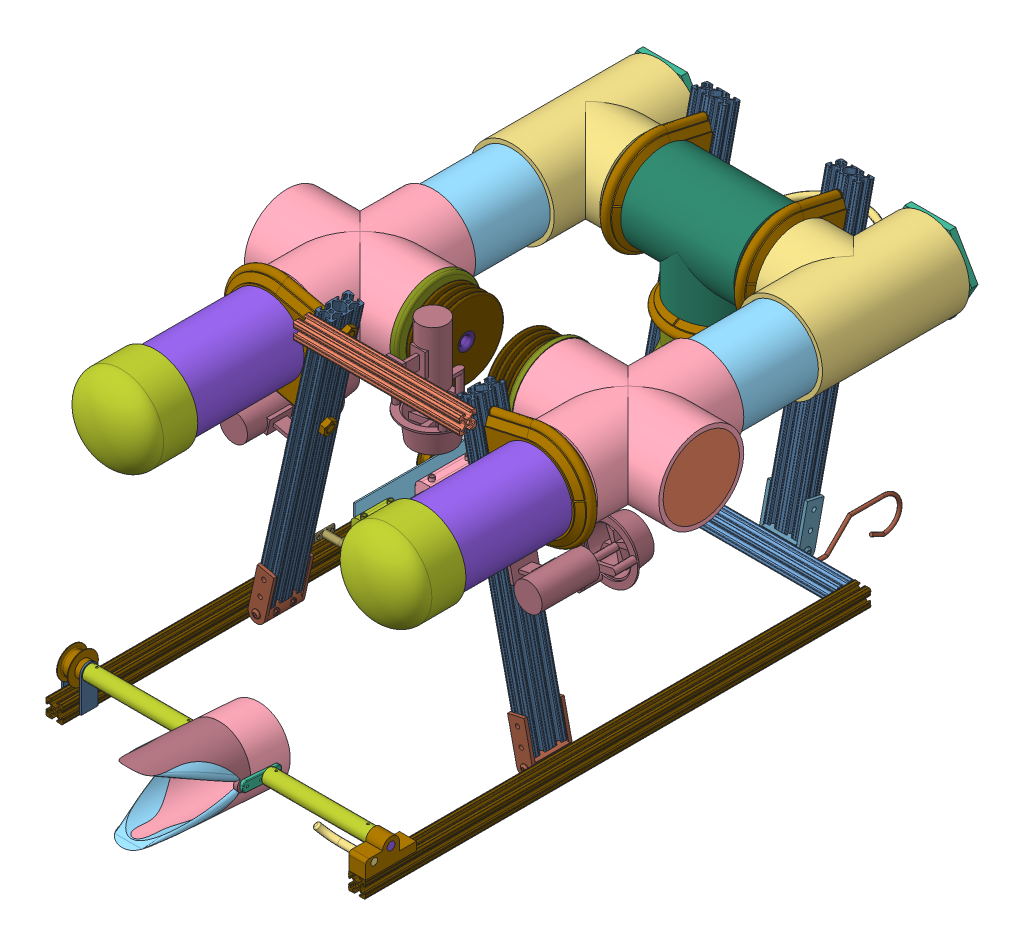
SolidWorks assembly Final_Model, configuration Default. Lengths in mm.
Overall size (623.28 474.95 1127.75).
98 component instances, 49 part files, 198 mates.
Components (placement in the parent):
- Camera-1: Camera [Default] at origin size (90 50 31)
- Camera_Lense-1: Camera_Lense [Default] at (45 25 12.5) size (114.76 114.76 10)
- PVC_Tee-2: PVC_Tee [4880K48] at (246.6576 226.6068 -97.99) x (0 0 1) z (0 -1 0) size (221.03 148.72 127.2)
- PVC_Tee-3: PVC_Tee [4880K48] at (-156.6576 226.6068 -97.99) x (0 0 -1) z (0 -1 0) size (221.03 148.72 127.2)
- PVC_Cross-1: PVC_Cross [4880K249] at (246.6576 226.6068 241.1708) x (1 -0.000013 0) z (0.000013 1 0) size (219.96 219.96 127.76)
- PVC_Cross-2: PVC_Cross [4880K249] at (-156.6576 226.6068 241.1708) x (1 0 0) z (0 1 0) size (219.96 219.96 127.76)
- Camera-2: Camera [Default] at (344.1393 201.6055 286.1708) x (0 0 -1) z (1 -0.000013 0) size (90 50 31)
- Camera_Lense-2: Camera_Lense [Default] at (346.6396 226.6055 241.1708) x (0 0 1) z (-1 0.000013 0) size (114.76 114.76 10)
- Camera-3: Camera [Default] at (-254.1396 201.6068 196.1708) x (0 0 1) z (-1 0 0) size (90 50 31)
- Camera_Lense-3: Camera_Lense [Default] at (-266.6396 226.6068 241.1708) x (0 0 1) z (-1 0 0) size (114.76 114.76 10)
- PVC_Pipe_SmallGap-1: PVC_Pipe_SmallGap [48925K98] at (-156.6576 226.6068 71.4888) size (114.3 114.3 221)
- PVC_Pipe_SmallGap-2: PVC_Pipe_SmallGap [48925K98] at (246.6576 226.6068 71.4888) x (-0.871628 0.490169 0) z (0 0 1) size (114.3 114.3 221)
- PVC_EndCap_Hex-1: PVC_EndCap_Hex [4880K851] at (246.6576 226.6068 -187.8679) x (0 0 -1) z (0.866025 -0.5 0) size (60.32 133.82 115.89)
- PVC_EndCap_Hex-2: PVC_EndCap_Hex [4880K851] at (-156.6576 226.6068 -187.8679) x (0 0 -1) z (0.866025 0.5 0) size (60.32 133.82 115.89)
- PVC_EndCap_Circle-3: PVC_EndCap_Circle [4880K58] at (-156.6576 226.6068 593.444) x (0 0 1) z (0.824445 0.565942 0) size (88.8 127.64 127.64)
- PVC_EndCap_Circle-4: PVC_EndCap_Circle [4880K58] at (246.6576 226.6068 593.444) x (0 0 1) z (0.198256 0.98015 0) size (88.8 127.64 127.64)
- PVC_Pipe_MedGap-1: PVC_Pipe_MedGap [48925K98] at (-156.6576 226.6068 450.3528) size (114.3 114.3 300)
- PVC_Pipe_MedGap-2: PVC_Pipe_MedGap [48925K98] at (246.6576 226.6068 450.3528) size (114.3 114.3 300)
- Ubolt_Clamp-1: Ubolt_Clamp [3176T41] at (-55.8634 205.2169 -194.7131) x (0 -0.976409 0.215928) z (-1 0 0) size (161.7 175.58 31.5)
- Ubolt_Clamp-2: Ubolt_Clamp [3176T41] at (145.8634 205.2169 -194.7131) x (0 0.976409 -0.215928) z (1 0 0) size (161.7 175.58 31.5)
- Ubolt_Clamp-3: Ubolt_Clamp [3176T41] at (-59.9348 205.2157 366.9008) x (-0.215941 -0.976406 0) z (0 0 -1) size (161.7 175.58 31.5)
- Ubolt_Clamp-4: Ubolt_Clamp [3176T41] at (149.9345 205.2169 366.9008) x (0.215928 -0.976409 0) z (0 0 1) size (161.7 175.58 31.5)
- 8020_Vertical_Bar-1: 8020_Vertical_Bar [47065T213] at (-154.2406 -116.7666 379.6008) x (0 0 -1) z (0.215941 0.976406 0) size (50.88 25.48 430)
- 8020_Vertical_Bar-2: 8020_Vertical_Bar [47065T213] at (244.236 -116.7665 354.2008) x (0 0 1) z (-0.215928 0.976409 0) size (50.88 25.48 430)
- 8020_Vertical_Bar-3: 8020_Vertical_Bar [47065T213] at (133.1634 -116.7665 -100.4116) x (1 0 0) z (0 0.976409 -0.215928) size (50.88 25.48 430)
- 8020_Vertical_Bar-4: 8020_Vertical_Bar [47065T213] at (-43.1634 -116.7665 -100.4116) x (-1 0 0) z (0 0.976409 -0.215928) size (50.88 25.48 430)
- 8020_Front_Hinge-1: 8020_Front_Hinge [47065T192] at (-156.8545 -130.0147 366.5923) x (-0.000013 -1 0) z (0 0 1) size (77.44 42.62 66.61)
- 8020_Front_Hinge-2: 8020_Front_Hinge [47065T192] at (246.8498 -130.0147 366.5923) x (0 -1 0) z (0 0 -1) size (77.44 42.62 66.61)
- Ubolt_Clamp-5: Ubolt_Clamp [3176T41] at (45 125.838 -197.05) x (1 0 0) z (0 -1 0) size (161.7 175.58 31.5)
- 8020_Rear_Thruster_Bar-1: 8020_Rear_Thruster_Bar [47065T213] at (-49.75 138.538 -174.4985) x (0 -1 0) z (1 0 0) size (50.88 25.6 169.85)
- Thruster-1: Thruster [Default] at (45.25 92.1765 -245.3518) x (1 0 0) z (0 -1 0) size (91 103.34 158.7)
- 8020_Rear_Hinge-1: 8020_Rear_Hinge [47065T192] at (-56.1719 -130.0147 -97.7978) x (0 1 0) z (-1 0 0) size (77.44 42.62 66.61)
- 8020_Rear_Hinge-2: 8020_Rear_Hinge [47065T192] at (146.1719 -130.0147 -97.7978) x (0 1 0) z (-1 0 0) size (77.44 42.62 66.61)
- PVC_Rear_Tee-1: PVC_Rear_Tee [4880K48] at (45 226.6068 -97.99) x (-1 0 0) z (0 0 1) size (170.23 148.72 127.2)
- PVC_Rear_Elbow-1: PVC_Rear_Elbow [4880K28] at (45 25 -97.99) x (0 0 -1) z (1 0 0) size (173.99 148.59 127)
- PVC_Pipe_Rear-1: PVC_Pipe_Rear [48925K98] at (45 125.778 -97.99) x (0.999631 0 -0.027178) z (0 1 0) size (114.3 114.3 83.7)
- PVC_Pipe_Rear-2: PVC_Pipe_Rear [48925K98] at (-55.8288 226.6068 -97.99) x (0 0 -1) z (1 0 0) size (114.3 114.3 83.7)
- PVC_Pipe_Rear-3: PVC_Pipe_Rear [48925K98] at (145.8288 226.6068 -97.99) x (0 -0.326039 -0.945356) z (1 0 0) size (114.3 114.3 83.7)
- 8020_Horizontal_Bar_Long-1: 8020_Horizontal_Bar_Long [47065T121] at (272.5583 -129.9315 294.9022) x (-1 0 0) z (0 0 -1) size (25.48 25.48 760)
- 8020_Horizontal_Bar_Long-2: 8020_Horizontal_Bar_Long [47065T121] at (-182.563 -130.3228 294.9022) x (-1 0.000013 0) z (0 0 -1) size (25.48 25.48 760)
- 8020_Rear_Bar-1: 8020_Rear_Bar [47065T121] at (44.9998 -129.9315 -72.6063) x (0 0 -1) z (1 0 0) size (25.48 25.48 429.1)
- 8020_Front_Thruster_Bar-1: 8020_Front_Thruster_Bar [47065T121] at (45.0956 287.4796 405.6178) x (0 0 1) z (-1 0.000013 0) size (25.48 25.48 250)
- Thruster-2: Thruster [Default] at (46.3449 241.1181 334.7645) x (1 -0.000013 0) z (-0.000013 -1 0) size (91 103.34 158.7)
- Thruster-3: Thruster [Default] at (266.4534 110.9017 324.7393) x (0.215928 -0.976409 0) z (0 0 -1) size (91 103.34 158.7)
- Thruster-4: Thruster [Default] at (-176.4549 110.902 324.7393) x (0.215941 0.976406 0) z (0 0 -1) size (91 103.34 158.7)
- Rear_Thruster_Protector_Bar-3: Rear_Thruster_Protector_Bar [Default] at (-25.1 146.5465 -192.507) size (150.2 10 130.1)
- Rear_Thruster_Protector_Bar-4: Rear_Thruster_Protector_Bar [Default] at (-25.1 105.1295 -192.507) size (150.2 10 130.1)
- Beakassem-1: Beakassem [Default] at (31.099 -354.5443 692.4929) x (-1 0 0) z (0 -0.071631 -0.997431) size (427.7 101.75 206.93)
  - bottombeaktube-3: bottombeaktube [Default] at (-15.2178 266.4346 -125.0001) size (101.75 101.75 206.93)
  - beakgums-3: beakgums [Default] at (-15.2178 266.4346 -125.0001) size (101.75 50.35 132.84)
  - cupbarconnector-1: cupbarconnector [Default] at (-66.0928 250.081 42.166) x (-1 0 0) z (0 0 -1) size (25 15 58.1)
  - cupbarconnector-2: cupbarconnector [Default] at (35.6572 282.7881 42.166) x (1 0 0) z (0 0 -1) size (25 15 58.1)
  - beakshaft-1: beakshaft [Default] at (40.6572 266.4346 36.6999) size (157.97 22 22)
  - beakshaft-2: beakshaft [Default] at (-229.0678 266.4346 36.6999) size (157.97 22 22)
- beakshaftrod-1: beakshaftrod [Default] at (285.5668 -91.423 636.8022) size (50.8 12 12)
- beakshaftholder-1: beakshaftholder [Default] at (260.1668 -91.423 636.8022) size (25.4 38.2 76.2)
- beakendcap-1: beakendcap [Default] at (46.3168 -94.0591 600.0968) x (0.980812 -0.194455 0.013965) z (0 0.071631 0.997431) size (89.8 89.8 10)
- Hook-1: Hook [Default] at (196.3344 -129.8147 -77.1148) x (0 -1 0) z (-1 0 0) size (55 142.87 5)
- Hook-2: Hook [Default] at (-103.6656 -129.8147 -77.1148) x (0 -1 0) z (-1 0 0) size (55 142.87 5)
- electronics_plate2-1: electronics_plate2 [Default] at (-18.4284 -61.9406 7.3582) x (0.558849 0.829269 0) z (0 0 1) size (90 20.96 469.2)
  - electronics_plate-2: electronics_plate [Default] at (117.0343 251.6082 591.6759) size (90 6.35 469.2)
  - ArduinoMega-2: ArduinoMega [Default] at (180.3262 259.6092 300.8759) x (0 0 -1) z (0 -1 0) size (107.95 53.42 12.95)
  - motor_controller-1: motor_controller [Default] at (140.6563 260.1796 216.7494) x (0 0 -1) z (1 0 0) size (58.55 14.61 47.24)
  - motor_controller-2: motor_controller [Default] at (140.6563 260.1796 385.2964) x (0 0 -1) z (1 0 0) size (58.55 14.61 47.24)
  - Accelerometer-1: Accelerometer [Default] at (196.2343 263.3582 197.7882) x (0 0 -1) z (1 0 0) size (39.4 10.8 21.6)
- heatsinkassem-1: heatsinkassem [Default] at (-27.1485 162.2777 98.211) size (60 145.3 145.3)
  - heatsinkcaps-1: heatsinkcaps [Default] at (-29.5271 64.3291 142.9598) size (20 129.7 129.7)
  - heatsinkbar-1: heatsinkbar [Default] at (-19.5271 64.3291 142.9598) size (50 25.4 25.4)
  - heatsinkdisc-1: heatsinkdisc [Default] at (-4.5271 64.3291 142.9598) x (1 0 0) z (0 -0.002531 0.999997) size (5 114.3 114.3)
  - heatsinkdisc-2: heatsinkdisc [Default] at (5.4729 64.3291 142.9598) x (1 0 0) z (0 -0.32571 0.94547) size (5 114.3 114.3)
  - heatsinkdisc-3: heatsinkdisc [Default] at (15.4729 64.3291 142.9598) x (1 0 0) z (0 -0.122449 0.992475) size (5 114.3 114.3)
  - heatsinkdisc-4: heatsinkdisc [Default] at (25.4729 64.3291 142.9598) x (1 0 0) z (0 -0.013398 0.99991) size (5 114.3 114.3)
- heatsinkassem-2: heatsinkassem [Default] at (117.1499 334.1715 355.2145) x (-1 0.000013 0) z (-0.000012 -0.924225 -0.381849) size (60 145.3 145.3)
  - heatsinkcaps-1: heatsinkcaps [Default] at (-29.5271 64.3291 142.9598) size (20 129.7 129.7)
  - heatsinkbar-1: heatsinkbar [Default] at (-19.5271 64.3291 142.9598) size (50 25.4 25.4)
  - heatsinkdisc-1: heatsinkdisc [Default] at (-4.5271 64.3291 142.9598) x (1 0 0) z (0 -0.002531 0.999997) size (5 114.3 114.3)
  - heatsinkdisc-2: heatsinkdisc [Default] at (5.4729 64.3291 142.9598) x (1 0 0) z (0 -0.32571 0.94547) size (5 114.3 114.3)
  - heatsinkdisc-3: heatsinkdisc [Default] at (15.4729 64.3291 142.9598) x (1 0 0) z (0 -0.122449 0.992475) size (5 114.3 114.3)
  - heatsinkdisc-4: heatsinkdisc [Default] at (25.4729 64.3291 142.9598) x (1 0 0) z (0 -0.013398 0.99991) size (5 114.3 114.3)
- beakcamera-1: beakcamera [Default] at (46.3168 -91.1938 639.994) x (-1 0 0) z (0 0.071631 0.997431) size (32 32 18.5)
- cam_extender-1: cam_extender [Default] at (46.3168 -93.3428 610.0711) x (1 -0.000009 0.000001) z (0 0.071631 0.997431) size (10 10 30)
- Sensor String Hook-1: Sensor String Hook [Default] at (285.5668 -95.0499 664.9022) x (-1 0 0) z (0 0.58 -0.814616) size (81.1 24.09 10.56)
- doublepiston1_2-1: doublepiston1_2 [Default] at (-149.5251 -180.8148 114.2685) x (-1 0.000013 0) z (0 0 -1) size (34.49 70 193)
  - piston2cylinder-1: piston2cylinder [Default] at (-14.4452 85 1.8662) size (30 35 85)
  - Lbracket-1: Lbracket [Default] at (-14.9529 40 69.3662) size (2 70 193)
- cyl2shaft-1: cyl2shaft [Default] at (-150.0789 -95.8148 196.5674) x (0.938347 -0.345695 0) z (0 0 -1) size (10 10 60.8)
- cyl1-1: cyl1 [Default] at (-135.1932 -95.815 221.5674) x (-1 0.000013 0) z (0 0 -1) size (30 35 60)
- cyl1shaft-1: cyl1shaft [Default] at (-150.1932 -95.8148 270.078) x (0.942292 0.334793 0) z (0 0 -1) size (10 10 35.4)
- pistonwheel-1: pistonwheel [Default] at (-178.5332 -91.423 636.8022) x (-1 0 0) z (0 0.722827 -0.691029) size (24.5 46 46)
- beakshaftrod-2: beakshaftrod [Default] at (-146.2332 -91.423 636.8022) x (1 0 0) z (0 0.000013 1) size (50.8 12 12)
- Piston_Side_Rod_Holder-1: Piston_Side_Rod_Holder [Default] at (-197.0332 -91.423 636.8022) x (0 -0.000206 -1) z (1 0 0) size (25.4 62.7 2.5)
- Piston_Side_Rod_Holder-2: Piston_Side_Rod_Holder [Default] at (-170.0332 -91.423 636.8022) x (0 -0.000206 -1) z (1 0 0) size (25.4 62.7 2.5)
- pistonwheel-2: pistonwheel [Default] at (-178.071 -91.3314 95.768) x (-1 0.000013 0) z (0 0 1) size (24.5 46 46)
- Piston_Side_Rod_Holder-3: Piston_Side_Rod_Holder [Default] at (-196.571 -91.3311 95.768) x (0 0 -1) z (1 -0.000013 0) size (25.4 62.7 2.5)
- pistonbeltconnector-3: pistonbeltconnector [Default] at (-165.0788 -90.8146 54.9022) x (-0.000013 -1 0) z (0 0 1) size (10 22.49 30)
- pistonbeltconnector2-1: pistonbeltconnector2 [Default] at (-175.1933 -100.8144 280.078) x (0.000013 1 0) z (0 0 -1) size (10 32.49 30)
- topbeak2-1: topbeak2 [Default] at (46.3168 -79.8402 798.0869) x (1 0 0) z (0 -0.071631 -0.997431) size (101.75 60.88 147.43)
- beakgums-1: beakgums [Default] at (46.3168 -79.8402 798.0869) x (1 0 0) z (0 -0.071631 -0.997431) size (101.75 50.35 132.84)
Mates (geometry in assembly coordinates):
- Perpendicular3: perpendicular: plane of PVC_Cross-1 through (310.5386 226.606 351.1528) normal (0 0 1); plane of PVC_Cross-2 through (-46.6756 226.6068 305.0518) normal (1 0 0)
- Distance4: distance = 12.5 mm aligned: plane of Camera-2 through (344.1393 201.6055 286.1708) normal (1 -0.000013 0); plane of PVC_Cross-1 through (356.6396 226.6054 305.0518) normal (1 -0.000013 0)
- Concentric17: concentric anti-aligned: circle of PVC_Cross-1; circle of Camera-2
- Perpendicular4: perpendicular: plane of PVC_Cross-1 through (356.6396 226.6054 305.0518) normal (1 -0.000013 0); plane of Camera-2 through (314.1393 201.6059 196.1708) normal (0 0 -1)
- Coincident30: coincident aligned: plane of PVC_Cross-1 through (356.6396 226.6054 305.0518) normal (1 -0.000013 0); plane of Camera_Lense-2 through (356.6396 226.6054 241.1708) normal (1 -0.000013 0)
- Concentric18: concentric aligned: cone of PVC_Cross-1 through (356.6396 226.6054 241.1708) axis (-1 0.000013 0); cylinder of Camera_Lense-2 through (356.6396 226.6054 241.1708) axis (-1 0.000013 0) radius 57.3785
- Distance5: distance = 12.5 mm aligned: plane of Camera-3 through (-254.1396 201.6068 196.1708) normal (-1 0 0); plane of PVC_Cross-2 through (-266.6396 226.6068 305.0518) normal (-1 0 0)
- Concentric19: concentric aligned: circle of PVC_Cross-2; circle of Camera-3
- Perpendicular5: perpendicular: plane of PVC_Cross-2 through (-266.6396 226.6068 305.0518) normal (-1 0 0); plane of Camera-3 through (-224.1396 201.6068 196.1708) normal (0 0 -1)
- Coincident33: coincident aligned: plane of PVC_Cross-2 through (-266.6396 226.6068 305.0518) normal (-1 0 0); plane of Camera_Lense-3 through (-266.6396 226.6068 241.1708) normal (-1 0 0)
- Concentric20: concentric anti-aligned: cone of PVC_Cross-2 through (-215.8396 226.6068 241.1708) axis (1 0 0); cylinder of Camera_Lense-3 through (-256.6396 226.6068 241.1708) axis (-1 0 0) radius 57.3785
- Coincident34: coincident anti-aligned: plane of PVC_Tee-3 through (-156.6576 226.6068 -39.0112) normal (0 0 1); plane of PVC_Pipe_SmallGap-1 through (-156.6576 226.6068 -39.0112) normal (0 0 -1)
- Concentric21: concentric aligned: cone of PVC_Tee-3 through (-156.6576 226.6068 -39.0112) axis (0 0 -1); cylinder of PVC_Pipe_SmallGap-1 through (-156.6576 226.6068 181.9888) axis (0 0 -1) radius 57.15
- Coincident35: coincident anti-aligned: plane of PVC_Cross-2 through (-156.6576 226.6068 181.9888) normal (0 0 -1); plane of PVC_Pipe_SmallGap-1 through (-156.6576 226.6068 181.9888) normal (0 0 1)
- Concentric22: concentric anti-aligned: cone of PVC_Cross-2 through (-156.6576 226.6068 131.1888) axis (0 0 1); cylinder of PVC_Pipe_SmallGap-1 through (-156.6576 226.6068 181.9888) axis (0 0 -1) radius 57.15
- Concentric23: concentric aligned: cone of PVC_Tee-2 through (246.6576 226.6068 12.5254) axis (0 0 -1); cylinder of PVC_Pipe_SmallGap-2 through (246.6576 226.6068 181.9888) axis (0 0 -1) radius 57.15
- Coincident36: coincident anti-aligned: plane of PVC_Tee-2 through (246.6576 226.6068 -39.0112) normal (0 0 1); plane of PVC_Pipe_SmallGap-2 through (246.6576 226.6068 -39.0112) normal (0 0 -1)
- Coincident37: coincident anti-aligned: plane of PVC_Cross-1 through (246.6576 226.6068 181.9888) normal (0 0 -1); plane of PVC_Pipe_SmallGap-2 through (246.6576 226.6068 181.9888) normal (0 0 1)
- Concentric24: concentric anti-aligned: cone of PVC_Cross-1 through (246.6576 226.6068 131.1888) axis (0 0 1); cylinder of PVC_Pipe_SmallGap-2 through (246.6576 226.6068 181.9888) axis (0 0 -1) radius 57.15
- Concentric25: concentric aligned: cone of PVC_Tee-3 through (-156.6576 226.6068 -208.5054) axis (0 0 1); cylinder of PVC_EndCap_Hex-2 through (-156.6576 226.6068 -157.7054) axis (0 0 1) radius 57.15
- Coincident38: coincident anti-aligned: plane of PVC_Tee-3 through (-220.2592 226.6068 -208.5054) normal (0 0 -1); plane of PVC_EndCap_Hex-2 through (-190.1114 284.5505 -208.5054) normal (0 0 1)
- Parallel6: parallel aligned: plane of Camera-1 through (0 50 -30) normal (0 1 0); plane of PVC_EndCap_Hex-2 through (-190.1114 284.5505 -208.5054) normal (0 1 0)
- Concentric26: concentric aligned: cone of PVC_Tee-2 through (246.6576 226.6068 -156.9688) axis (0 0 1); cylinder of PVC_EndCap_Hex-1 through (246.6576 226.6068 -157.7054) axis (0 0 1) radius 57.15
- Coincident43: coincident anti-aligned: plane of PVC_Tee-2 through (310.2592 226.6068 -208.5054) normal (0 0 -1); plane of PVC_EndCap_Hex-1 through (280.1114 284.5505 -208.5054) normal (0 0 1)
- Coincident44: coincident aligned: plane of PVC_EndCap_Hex-1 through (213.2038 284.5505 -208.5054) normal (0 1 0); plane of PVC_EndCap_Hex-2 through (-190.1114 284.5505 -208.5054) normal (0 1 0)
- Concentric36: concentric aligned: cone of PVC_Cross-2 through (-156.6576 226.6068 300.3528) axis (0 0 -1); cylinder of PVC_Pipe_MedGap-1 through (-156.6576 226.6068 600.3528) axis (0 0 -1) radius 57.15
- Concentric37: concentric anti-aligned: cone of PVC_EndCap_Circle-3 through (-156.6576 226.6068 600.3528) axis (0 0 1); cylinder of PVC_Pipe_MedGap-1 through (-156.6576 226.6068 600.3528) axis (0 0 -1) radius 57.15
- Coincident55: coincident anti-aligned: circle of PVC_EndCap_Circle-3; plane of PVC_Pipe_MedGap-1 through (-156.6576 226.6068 600.3528) normal (0 0 1)
- Coincident56: coincident anti-aligned: plane of PVC_Cross-2 through (-156.6576 226.6068 300.3528) normal (0 0 1); plane of PVC_Pipe_MedGap-1 through (-156.6576 226.6068 300.3528) normal (0 0 -1)
- Concentric38: concentric aligned: cone of PVC_Cross-1 through (246.6576 226.6068 300.3528) axis (0 0 -1); cylinder of PVC_Pipe_MedGap-2 through (246.6576 226.6068 600.3528) axis (0 0 -1) radius 57.15
- Concentric39: concentric anti-aligned: cone of PVC_EndCap_Circle-4 through (246.6576 226.6068 600.3528) axis (0 0 1); cylinder of PVC_Pipe_MedGap-2 through (246.6576 226.6068 600.3528) axis (0 0 -1) radius 57.15
- Coincident57: coincident anti-aligned: circle of PVC_EndCap_Circle-4; plane of PVC_Pipe_MedGap-2 through (246.6576 226.6068 600.3528) normal (0 0 1)
- Coincident58: coincident anti-aligned: plane of PVC_Cross-1 through (246.6576 226.6068 300.3528) normal (0 0 1); plane of PVC_Pipe_MedGap-2 through (246.6576 226.6068 300.3528) normal (0 0 -1)
- Parallel7: parallel aligned: plane of Ubolt_Clamp-1 through (-55.8634 144.6932 -144.9094) normal (0 -0.215928 -0.976409); plane of Ubolt_Clamp-2 through (145.8634 281.0975 -175.0746) normal (0 -0.215928 -0.976409)
- Concentric46: concentric anti-aligned: cylinder of PVC_Pipe_MedGap-2 through (246.6576 226.6068 600.3528) axis (0 0 -1) radius 57.15; cylinder of Ubolt_Clamp-4 through (246.6576 226.6068 351.1528) axis (0 0 1) radius 57.15
- Concentric47: concentric aligned: cylinder of PVC_Pipe_MedGap-1 through (-156.6576 226.6068 600.3528) axis (0 0 -1) radius 57.15; cylinder of Ubolt_Clamp-3 through (-156.6576 226.6068 382.6488) axis (0 0 -1) radius 57.15
- Parallel12: parallel aligned: plane of Ubolt_Clamp-3 through (-155.972 229.7069 382.6488) normal (0 0 1); plane of Ubolt_Clamp-4 through (233.7273 285.0764 382.6488) normal (0 0 1)
- Concentric48: concentric anti-aligned: circle of Ubolt_Clamp-3; cylinder of 8020_Vertical_Bar-1 through (-54.4704 275.545 366.9008) axis (-0.976406 0.215941 0) radius 6.75
- Distance7: distance = 8.5 mm anti-aligned: plane of 8020_Vertical_Bar-1 through (-65.7879 304.0617 380.7161) normal (-0.976406 0.215941 0); plane of Ubolt_Clamp-3 through (-109.7393 144.6925 366.9008) normal (0.976406 -0.215941 0)
- Parallel13: parallel aligned: plane of Ubolt_Clamp-3 through (-155.972 229.7069 382.6488) normal (0 0 1); plane of 8020_Vertical_Bar-1 through (-60.2968 302.8473 384.1093) normal (0 0 1)
- Concentric49: concentric anti-aligned: circle of Ubolt_Clamp-4; cylinder of 8020_Vertical_Bar-2 through (144.471 275.5463 366.9008) axis (0.976409 0.215928 0) radius 6.75
- Distance8: distance = 8.5 mm anti-aligned: plane of 8020_Vertical_Bar-2 through (155.789 304.0629 353.0855) normal (0.976409 0.215928 0); plane of Ubolt_Clamp-4 through (199.7382 144.6932 366.9008) normal (-0.976409 -0.215928 0)
- Parallel14: parallel aligned: plane of Ubolt_Clamp-4 through (245.972 229.7069 351.1528) normal (0 0 -1); plane of 8020_Vertical_Bar-2 through (150.2978 302.8486 349.6923) normal (0 0 -1)
- Concentric50: concentric anti-aligned: circle of Ubolt_Clamp-2; cylinder of 8020_Vertical_Bar-3 through (145.8634 281.0309 -175.3758) axis (0 -0.215928 -0.976409) radius 6.75
- Distance9: distance = 8.5 mm anti-aligned: plane of 8020_Vertical_Bar-3 through (159.6787 304.0629 -188.8586) normal (0 0.215928 0.976409); plane of Ubolt_Clamp-2 through (145.8634 281.0975 -175.0746) normal (0 -0.215928 -0.976409)
- Parallel15: parallel aligned: plane of Ubolt_Clamp-2 through (130.1154 223.5067 -97.3044) normal (-1 0 0); plane of 8020_Vertical_Bar-3 through (128.6549 303.3302 -192.1718) normal (-1 0 0)
- Concentric51: concentric anti-aligned: circle of Ubolt_Clamp-1; cylinder of 8020_Vertical_Bar-4 through (-55.8634 275.5463 -200.1766) axis (0 0.215928 0.976409) radius 6.75
- Distance10: distance = 8.5 mm anti-aligned: plane of 8020_Vertical_Bar-4 through (-69.6787 304.0629 -188.8586) normal (0 0.215928 0.976409); plane of Ubolt_Clamp-1 through (-55.8634 144.6932 -144.9094) normal (0 -0.215928 -0.976409)
- Parallel16: parallel aligned: plane of Ubolt_Clamp-1 through (-71.6114 285.0764 -110.9203) normal (-1 0 0); plane of 8020_Vertical_Bar-4 through (-73.0719 302.8486 -194.3498) normal (-1 0 0)
- Parallel17: parallel aligned: plane of 8020_Vertical_Bar-3 through (132.0481 302.1159 -197.6629) normal (0 -0.215928 -0.976409); plane of 8020_Vertical_Bar-4 through (-42.0481 302.1159 -197.6629) normal (0 -0.215928 -0.976409)
- Distance11: distance = 100 mm: moEndPointRef_w of 8020_Vertical_Bar-2; plane of PVC_Cross-1 through (356.6396 226.6054 305.0518) normal (1 -0.000013 0)
- Distance12: distance = 100 mm: plane of PVC_Cross-2 through (-266.6396 226.6068 305.0518) normal (-1 0 0); moEndPointRef_w of 8020_Vertical_Bar-1
- Distance13: distance = 8.5 mm anti-aligned: plane of 8020_Front_Hinge-1 through (-156.8545 -130.0147 341.1923) normal (0 0 1); plane of 8020_Vertical_Bar-1 through (-60.2968 302.8473 349.6923) normal (0 0 -1)
- Distance14: distance = 50 mm anti-aligned: plane of 8020_Front_Hinge-1 through (-155.5426 -65.2704 396.7548) normal (0.215941 0.976406 0); plane of 8020_Vertical_Bar-1 through (-164.4833 -114.5013 390.091) normal (-0.215941 -0.976406 0)
- Distance15: distance = 8.5 mm aligned: plane of 8020_Front_Hinge-1 through (-130.7419 -70.7553 396.7548) normal (0.976406 -0.215941 0); plane of 8020_Vertical_Bar-1 through (-56.9837 302.1146 380.7161) normal (0.976406 -0.215941 0)
- Distance16: distance = 8.5 mm anti-aligned: plane of 8020_Front_Hinge-2 through (246.8498 -130.0147 341.1923) normal (0 0 1); plane of 8020_Vertical_Bar-2 through (150.2978 302.8486 349.6923) normal (0 0 -1)
- Distance17: distance = 50 mm anti-aligned: plane of 8020_Front_Hinge-2 through (245.5388 -65.2704 336.4298) normal (-0.215928 0.976409 0); plane of 8020_Vertical_Bar-2 through (254.4788 -114.5014 343.7106) normal (0.215928 -0.976409 0)
- Distance18: distance = 8.5 mm aligned: plane of 8020_Front_Hinge-2 through (220.738 -70.755 336.4298) normal (-0.976409 -0.215928 0); plane of 8020_Vertical_Bar-2 through (146.9847 302.1159 353.0855) normal (-0.976409 -0.215928 0)
- Parallel19: parallel aligned: plane of PVC_EndCap_Hex-2 through (-156.6576 226.6068 -218.0304) normal (0 0 -1); plane of Ubolt_Clamp-5 through (114.85 125.838 -161.49) normal (0 0 -1)
- Concentric53: concentric anti-aligned: circle of Ubolt_Clamp-5; cylinder of 8020_Rear_Thruster_Bar-1 through (114.85 125.838 -161.7985) axis (0 0 -1) radius 6.75
- Parallel20: parallel aligned: plane of Ubolt_Clamp-5 through (41.825 141.586 -97.99) normal (0 1 0); plane of 8020_Rear_Thruster_Bar-1 through (140.25 143.0465 -173.3832) normal (0 1 0)
- Distance25: distance = 8.5 mm anti-aligned: plane of 8020_Rear_Thruster_Bar-1 through (140.25 139.6533 -169.99) normal (0 0 1); plane of Ubolt_Clamp-5 through (114.85 125.838 -161.49) normal (0 0 -1)
- Distance26: distance = 8.5 mm anti-aligned: plane of Thruster-1 through (45.25 92.1765 -187.507) normal (0 0 1); plane of 8020_Rear_Thruster_Bar-1 through (140.25 112.0227 -179.007) normal (0 0 -1)
- Distance27: distance = 8.5 mm aligned: plane of Thruster-1 through (32.75 151.5465 -187.507) normal (0 1 0); plane of 8020_Rear_Thruster_Bar-1 through (140.25 143.0465 -173.3832) normal (0 1 0)
- Distance31: distance = 8.5 mm anti-aligned: plane of 8020_Vertical_Bar-4 through (-73.0719 302.8486 -194.3498) normal (-1 0 0); plane of 8020_Rear_Hinge-1 through (-81.5719 -130.0147 -97.7978) normal (1 0 0)
- Distance29: distance = 50 mm anti-aligned: plane of 8020_Rear_Hinge-1 through (-86.3344 -70.755 -123.9096) normal (0 0.976409 -0.215928); plane of 8020_Vertical_Bar-4 through (-32.6732 -114.5014 -90.1688) normal (0 -0.976409 0.215928)
- Distance30: distance = 8.5 mm aligned: plane of 8020_Rear_Hinge-1 through (-26.0094 -132.757 -110.1982) normal (0 -0.215928 -0.976409); plane of 8020_Vertical_Bar-4 through (-69.6787 302.1159 -197.6629) normal (0 -0.215928 -0.976409)
- Distance33: distance = 50 mm anti-aligned: plane of 8020_Rear_Hinge-2 through (176.3344 -70.755 -123.9096) normal (0 0.976409 -0.215928); plane of 8020_Vertical_Bar-3 through (122.6732 -119.0317 -110.6543) normal (0 -0.976409 0.215928)
- Distance34: distance = 8.5 mm aligned: plane of 8020_Rear_Hinge-2 through (176.3344 -132.757 -110.1982) normal (0 -0.215928 -0.976409); plane of 8020_Vertical_Bar-3 through (159.6787 302.1159 -197.6629) normal (0 -0.215928 -0.976409)
- Coincident99: coincident anti-aligned: plane of PVC_Cross-2 through (-92.7766 226.6068 351.1528) normal (0 0 1); plane of Ubolt_Clamp-3 through (-143.7265 285.0763 351.1528) normal (0 0 -1)
- Coincident100: coincident anti-aligned: plane of PVC_Cross-1 through (310.5386 226.606 351.1528) normal (0 0 1); plane of Ubolt_Clamp-4 through (245.972 229.7069 351.1528) normal (0 0 -1)
- Coincident110: coincident aligned: circle of Camera_Lense-1; plane of PVC_Rear_Elbow-1 through (45 -38.5 12.5) normal (0 0 1)
- Concentric58: concentric anti-aligned: cylinder of Camera_Lense-1 through (45 25 2.5) axis (0 0 1) radius 57.3785; cone of PVC_Rear_Elbow-1 through (45 25 -39.062) axis (0 0 -1)
- Perpendicular6: perpendicular: plane of Ubolt_Clamp-2 through (130.1154 223.5067 -97.3044) normal (-1 0 0); plane of PVC_Rear_Elbow-1 through (45 -38.5 12.5) normal (0 0 1)
- Distance35: distance = 12.5 mm aligned: plane of Camera-1 through (0 0 0) normal (0 0 1); plane of PVC_Rear_Elbow-1 through (45 -38.5 12.5) normal (0 0 1)
- Concentric59: concentric aligned: circle of Camera-1; circle of PVC_Rear_Elbow-1
- Concentric60: concentric aligned: cone of PVC_Rear_Elbow-1 through (45 135.49 -97.99) axis (0 -1 0); cylinder of PVC_Pipe_Rear-1 through (45 167.628 -97.99) axis (0 -1 0) radius 57.15
- Coincident115: coincident anti-aligned: plane of PVC_Rear_Elbow-1 through (45 83.928 -97.99) normal (0 1 0); plane of PVC_Pipe_Rear-1 through (45 83.928 -97.99) normal (0 -1 0)
- Coincident116: coincident anti-aligned: plane of Ubolt_Clamp-5 through (-14.8823 110.09 -97.99) normal (0 -1 0); plane of PVC_Rear_Elbow-1 through (45 110.09 -97.99) normal (0 1 0)
- Coincident117: coincident anti-aligned: plane of PVC_Rear_Tee-1 through (45 167.628 -97.99) normal (0 -1 0); plane of PVC_Pipe_Rear-1 through (45 167.628 -97.99) normal (0 1 0)
- Parallel26: parallel anti-aligned: plane of 8020_Rear_Thruster_Bar-1 through (140.25 112.0227 -179.007) normal (0 0 -1); plane of PVC_Rear_Elbow-1 through (45 -38.5 12.5) normal (0 0 1)
- Concentric61: concentric aligned: cylinder of Ubolt_Clamp-5 through (45 141.586 -97.99) axis (0 -1 0) radius 57.15; cylinder of PVC_Pipe_Rear-1 through (45 167.628 -97.99) axis (0 -1 0) radius 57.15
- Concentric62: concentric anti-aligned: cone of PVC_Rear_Tee-1 through (45 116.0914 -97.99) axis (0 1 0); cylinder of PVC_Pipe_Rear-1 through (45 167.628 -97.99) axis (0 -1 0) radius 57.15
- Concentric64: concentric aligned: cone of PVC_Tee-3 through (-46.1422 226.6068 -97.99) axis (-1 0 0); cylinder of PVC_Pipe_Rear-2 through (-13.9788 226.6068 -97.99) axis (-1 0 0) radius 57.15
- Concentric65: concentric aligned: cylinder of Ubolt_Clamp-1 through (-40.1154 226.6068 -97.99) axis (-1 0 0) radius 57.15; cylinder of PVC_Pipe_Rear-2 through (-13.9788 226.6068 -97.99) axis (-1 0 0) radius 57.15
- Concentric66: concentric anti-aligned: cone of PVC_Rear_Tee-1 through (-65.5154 226.6068 -97.99) axis (1 0 0); cylinder of PVC_Pipe_Rear-2 through (-13.9788 226.6068 -97.99) axis (-1 0 0) radius 57.15
- Coincident119: coincident anti-aligned: plane of PVC_Rear_Tee-1 through (-13.9788 226.6068 -97.99) normal (-1 0 0); plane of PVC_Pipe_Rear-2 through (-13.9788 226.6068 -97.99) normal (1 0 0)
- Coincident120: coincident anti-aligned: plane of PVC_Tee-3 through (-97.6788 226.6068 -97.99) normal (1 0 0); plane of PVC_Pipe_Rear-2 through (-97.6788 226.6068 -97.99) normal (-1 0 0)
- Coincident121: coincident anti-aligned: plane of Ubolt_Clamp-1 through (-40.1154 229.7069 -98.6756) normal (1 0 0); plane of PVC_Rear_Tee-1 through (-40.1154 226.6068 -97.99) normal (-1 0 0)
- Concentric67: concentric aligned: cone of PVC_Rear_Tee-1 through (103.9788 226.6068 -97.99) axis (-1 0 0); cylinder of PVC_Pipe_Rear-3 through (187.6788 226.6068 -97.99) axis (-1 0 0) radius 57.15
- Concentric68: concentric anti-aligned: cylinder of Ubolt_Clamp-2 through (130.1154 226.6068 -97.99) axis (1 0 0) radius 57.15; cylinder of PVC_Pipe_Rear-3 through (187.6788 226.6068 -97.99) axis (-1 0 0) radius 57.15
- Concentric69: concentric anti-aligned: cone of PVC_Tee-2 through (136.1422 226.6068 -97.99) axis (1 0 0); cylinder of PVC_Pipe_Rear-3 through (187.6788 226.6068 -97.99) axis (-1 0 0) radius 57.15
- Coincident122: coincident anti-aligned: plane of PVC_Tee-2 through (187.6788 226.6068 -97.99) normal (-1 0 0); plane of PVC_Pipe_Rear-3 through (187.6788 226.6068 -97.99) normal (1 0 0)
- Coincident123: coincident anti-aligned: plane of PVC_Rear_Tee-1 through (103.9788 226.6068 -97.99) normal (1 0 0); plane of PVC_Pipe_Rear-3 through (103.9788 226.6068 -97.99) normal (-1 0 0)
- Coincident124: coincident anti-aligned: plane of Ubolt_Clamp-2 through (130.1154 223.5067 -97.3044) normal (-1 0 0); plane of PVC_Rear_Tee-1 through (130.1154 226.6068 -97.99) normal (1 0 0)
- Distance36: distance = 8.5 mm anti-aligned: plane of 8020_Horizontal_Bar_Long-1 through (268.0498 -131.0468 -85.0978) normal (-1 0 0); plane of 8020_Front_Hinge-2 through (259.5498 -117.3147 341.1923) normal (1 0 0)
- Coincident132: coincident: line of 8020_Rear_Hinge-2 through (171.5719 -142.7147 -85.0978) axis (0 1 0); plane of 8020_Horizontal_Bar_Long-1 through (283.0485 -119.4413 -85.0978) normal (0 0 -1)
- Distance38: distance = 8.5 mm anti-aligned: plane of 8020_Horizontal_Bar_Long-2 through (-178.0546 -131.4382 -85.0978) normal (1 -0.000013 0); plane of 8020_Front_Hinge-1 through (-169.5544 -117.3145 391.9923) normal (-1 0.000013 0)
- Coincident135: coincident: line of 8020_Rear_Hinge-1 through (-81.5719 -142.7147 -85.0978) axis (0 1 0); plane of 8020_Horizontal_Bar_Long-2 through (-172.0727 -119.8328 -85.0978) normal (0 0 -1)
- Distance39: distance = 8.5 mm: plane of 8020_Horizontal_Bar_Long-2 through (-181.4477 -125.8143 -85.0978) normal (0.000013 1 0); line of 8020_Front_Hinge-1 through (-169.5544 -117.3145 391.9923) axis (0 0 -1)
- Distance40: distance = 8.5 mm anti-aligned: plane of 8020_Rear_Bar-1 through (259.5498 -119.4413 -62.1161) normal (1 0 0); plane of 8020_Horizontal_Bar_Long-1 through (268.0498 -131.0468 -85.0978) normal (-1 0 0)
- Coincident139: coincident aligned: plane of 8020_Horizontal_Bar_Long-1 through (273.6736 -125.423 -85.0978) normal (0 1 0); plane of 8020_Rear_Bar-1 through (259.5498 -125.423 -71.491) normal (0 1 0)
- Distance41: distance = 17 mm anti-aligned: plane of 8020_Rear_Bar-1 through (259.5498 -131.0468 -68.0978) normal (0 0 1); plane of 8020_Horizontal_Bar_Long-2 through (-172.0727 -119.8328 -85.0978) normal (0 0 -1)
- Coincident144: coincident: line of 8020_Rear_Hinge-2 through (120.7719 -117.3147 -85.0978) axis (1 0 0); moEndPointRef_w of 8020_Horizontal_Bar_Long-1
- Distance43: distance = 17 mm anti-aligned: plane of 8020_Front_Thruster_Bar-1 through (-79.9045 286.366 401.1093) normal (0 0 -1); plane of 8020_Vertical_Bar-2 through (150.2978 302.8486 384.1093) normal (0 0 1)
- Distance44: distance = 8.5 mm: plane of 8020_Front_Thruster_Bar-1 through (-79.9044 291.9898 404.5025) normal (0.000013 1 0); moEndPointRef_w of 8020_Vertical_Bar-2
- Distance45: distance = 6.75 mm: plane of 8020_Front_Thruster_Bar-1 through (-79.9043 297.9715 395.1276) normal (-1 0.000013 0); moEndPointRef_w of 8020_Vertical_Bar-1
- Distance46: distance = 8.5 mm anti-aligned: plane of Thruster-2 through (46.3449 241.1181 392.6093) normal (0 0 1); plane of 8020_Front_Thruster_Bar-1 through (-79.9045 286.366 401.1093) normal (0 0 -1)
- Distance47: distance = 8.5 mm aligned: plane of Thruster-2 through (33.8457 300.4883 392.6093) normal (0.000013 1 0); plane of 8020_Front_Thruster_Bar-1 through (-79.9044 291.9898 404.5025) normal (0.000013 1 0)
- Distance48: distance = 113.75 mm aligned: plane of Thruster-2 through (33.8457 300.4883 392.6093) normal (-1 0.000013 0); plane of 8020_Front_Thruster_Bar-1 through (-79.9043 297.9715 395.1276) normal (-1 0.000013 0)
- Distance50: distance = 8.5 mm anti-aligned: plane of 8020_Vertical_Bar-2 through (155.789 304.0629 380.7161) normal (0.976409 0.215928 0); plane of Thruster-3 through (209.9732 98.4114 324.7393) normal (-0.976409 -0.215928 0)
- Coincident152: coincident aligned: plane of 8020_Vertical_Bar-2 through (150.2978 302.8486 384.1093) normal (0 0 1); plane of Thruster-3 through (207.2741 110.6165 384.1093) normal (0 0 1)
- Distance49: distance = 200 mm aligned: plane of Thruster-3 through (207.2741 110.6165 384.1093) normal (-0.215928 0.976409 0); plane of 8020_Vertical_Bar-2 through (161.6295 305.3546 343.7106) normal (-0.215928 0.976409 0)
- Distance51: distance = 8.5 mm anti-aligned: plane of Thruster-4 through (-119.9749 98.4109 324.7393) normal (0.976406 -0.215941 0); plane of 8020_Vertical_Bar-1 through (-65.7879 304.0617 380.7161) normal (-0.976406 0.215941 0)
- Coincident155: coincident aligned: plane of 8020_Vertical_Bar-1 through (-60.2968 302.8473 384.1093) normal (0 0 1); plane of Thruster-4 through (-122.6742 86.2058 384.1093) normal (0 0 1)
- Distance52: distance = 200 mm aligned: plane of Thruster-4 through (-117.2756 110.616 384.1093) normal (0.215941 0.976406 0); plane of 8020_Vertical_Bar-1 through (-71.6285 305.3534 390.091) normal (0.215941 0.976406 0)
- Distance56: distance = 8.5 mm anti-aligned: plane of Rear_Thruster_Protector_Bar-3 through (-25.1 146.5465 -187.507) normal (0 0 1); plane of 8020_Rear_Thruster_Bar-1 through (140.25 139.6533 -179.007) normal (0 0 -1)
- Distance57: distance = 8.5 mm aligned: plane of Rear_Thruster_Protector_Bar-3 through (110.1 151.5465 -187.507) normal (0 1 0); plane of 8020_Rear_Thruster_Bar-1 through (140.25 143.0465 -173.3832) normal (0 1 0)
- Coincident172: coincident aligned: plane of 8020_Rear_Thruster_Bar-1 through (120.1 165.2683 -151.7998) normal (1 0 0); plane of Rear_Thruster_Protector_Bar-3 through (120.1 141.5465 -187.507) normal (1 0 0)
- Coincident173: coincident aligned: plane of Rear_Thruster_Protector_Bar-3 through (120.1 141.5465 -187.507) normal (1 0 0); plane of Rear_Thruster_Protector_Bar-4 through (120.1 100.1295 -187.507) normal (1 0 0)
- Coincident174: coincident aligned: plane of Rear_Thruster_Protector_Bar-3 through (-25.1 146.5465 -192.507) normal (0 0 -1); plane of Rear_Thruster_Protector_Bar-4 through (-25.1 105.1295 -192.507) normal (0 0 -1)
- Distance59: distance = 8.5 mm aligned: plane of Rear_Thruster_Protector_Bar-4 through (110.1 100.1295 -187.507) normal (0 -1 0); plane of 8020_Rear_Thruster_Bar-1 through (140.25 108.6295 -173.3832) normal (0 -1 0)
- Perpendicular7: perpendicular: plane of PVC_Rear_Elbow-1 through (45 -38.5 12.5) normal (0 0 1); plane of 8020_Front_Thruster_Bar-1 through (170.0957 297.9682 395.1276) normal (1 -0.000013 0)
- Perpendicular8: perpendicular: plane of PVC_Cross-1 through (356.6396 226.6054 305.0518) normal (1 -0.000013 0); plane of 8020_Front_Thruster_Bar-1 through (-79.9044 291.9898 404.5025) normal (0.000013 1 0)
- Concentric70: concentric aligned: cylinder of Beakassem-1/beakshaft-2 through (102.1918 -91.423 636.8022) axis (1 0 0) radius 6; cylinder of beakshaftrod-1 through (234.7668 -91.423 636.8022) axis (1 0 0) radius 6
- Distance68: distance = 25.4 mm aligned: plane of beakshaftrod-1 through (285.5668 -91.423 636.8022) normal (1 0 0); plane of Beakassem-1/beakshaft-2 through (260.1668 -91.423 636.8022) normal (1 0 0)
- Distance70: distance = 8.5 mm anti-aligned: plane of beakshaftholder-1 through (285.5668 -116.923 598.7022) normal (0 -1 0); plane of 8020_Horizontal_Bar_Long-1 through (273.6736 -125.423 -85.0978) normal (0 1 0)
- Distance71: distance = 8.5 mm aligned: plane of beakshaftholder-1 through (285.5668 -91.423 636.8022) normal (1 0 0); plane of 8020_Horizontal_Bar_Long-1 through (277.0668 -131.0468 -85.0978) normal (1 0 0)
- Coincident194: coincident aligned: plane of 8020_Horizontal_Bar_Long-1 through (283.0485 -119.4413 674.9022) normal (0 0 1); plane of beakshaftholder-1 through (285.5668 -116.923 674.9022) normal (0 0 1)
- Concentric72: concentric aligned: cylinder of beakshaftrod-1 through (234.7668 -91.423 636.8022) axis (1 0 0) radius 6; cylinder of beakshaftholder-1 through (260.1668 -91.423 636.8022) axis (1 0 0) radius 6
- Coincident195: coincident aligned: plane of beakshaftrod-1 through (285.5668 -91.423 636.8022) normal (1 0 0); circle of beakshaftholder-1
- Concentric76: concentric anti-aligned: cylinder of Beakassem-1/bottombeaktube-3 through (46.3168 -98.3211 540.7496) axis (0 0.071631 0.997431) radius 44.875; cylinder of beakendcap-1 through (46.3168 -93.3428 610.0711) axis (0 -0.071631 -0.997431) radius 44.9
- Coincident200: coincident aligned: plane of Beakassem-1/bottombeaktube-3 through (97.1918 -43.3148 596.4525) normal (0 -0.071631 -0.997431); plane of beakendcap-1 through (46.3168 -94.0591 600.0968) normal (0 -0.071631 -0.997431)
- Distance72: distance = 300 mm: point of Hook-1; point of Hook-2
- Coincident213: coincident aligned: plane of Hook-1 through (196.3344 -129.8147 -77.1148) normal (0 0 1); plane of Hook-2 through (-103.6656 -129.8147 -77.1148) normal (0 0 1)
- Parallel34: parallel aligned: plane of Hook-1 through (196.3344 -137.9915 -173.3804) normal (0 0.43589 0.9); plane of Hook-2 through (-103.6656 -137.9915 -173.3804) normal (0 0.43589 0.9)
- Coincident228: coincident anti-aligned: plane of 8020_Rear_Bar-1 through (259.5498 -131.0468 -77.1148) normal (0 0 -1); plane of Hook-1 through (196.3344 -129.8147 -77.1148) normal (0 0 1)
- Distance75: distance = 12.5 mm: line of Hook-1 through (196.3344 -129.8147 -77.1148) axis (0 0 -1); plane of 8020_Rear_Hinge-2 through (120.7719 -117.3147 -85.0978) normal (0 1 0)
- Distance76: distance = 12.5 mm: line of Hook-2 through (-103.6656 -129.8147 -77.1148) axis (0 0 -1); plane of 8020_Rear_Hinge-1 through (-81.5719 -117.3147 -85.0978) normal (0 1 0)
- Distance80: distance = 8.5 mm anti-aligned: plane of 8020_Rear_Hinge-2 through (171.5719 -130.0147 -97.7978) normal (-1 0 0); plane of 8020_Vertical_Bar-3 through (163.0719 303.3302 -192.1718) normal (1 0 0)
- Distance81: distance = 20 mm: line of Hook-1 through (196.3344 -129.8147 -77.1148) axis (0 0 -1); plane of 8020_Rear_Hinge-2 through (176.3344 -130.0147 -97.7978) normal (1 0 0)
- Coincident229: coincident: cylinder of PVC_Pipe_MedGap-1 through (-156.6576 226.6068 600.3528) axis (0 0 -1) radius 51.1302; line of electronics_plate2-1/electronics_plate-2 through (-161.6749 175.7234 129.834) axis (0 0 1)
- Coincident230: coincident: cylinder of PVC_Pipe_MedGap-1 through (-156.6576 226.6068 600.3528) axis (0 0 -1) radius 51.1302; line of electronics_plate2-1/electronics_plate-2 through (-111.3785 250.3576 599.034) axis (0 0 -1)
- Concentric80: concentric aligned: cone of PVC_Cross-2 through (-46.6756 226.6068 241.1708) axis (-1 0 0); cylinder of heatsinkassem-1/heatsinkcaps-1 through (-46.6756 226.6068 241.1708) axis (-1 0 0) radius 51.15
- Coincident231: coincident anti-aligned: plane of PVC_Cross-2 through (-46.6756 226.6068 305.0518) normal (1 0 0); plane of heatsinkassem-1/heatsinkcaps-1 through (-46.6756 226.6068 241.1708) normal (-1 0 0)
- Concentric82: concentric aligned: cone of PVC_Cross-1 through (187.4756 226.6076 241.1708) axis (1 -0.000013 0); cylinder of heatsinkassem-2/heatsinkcaps-1 through (136.6756 226.6082 241.1708) axis (1 -0.000013 0) radius 51.15
- Coincident232: coincident anti-aligned: plane of PVC_Cross-1 through (136.6756 226.6082 305.0518) normal (-1 0.000013 0); plane of heatsinkassem-2/heatsinkcaps-1 through (136.6756 226.6082 241.1708) normal (1 -0.000013 0)
- Concentric83: concentric anti-aligned: cylinder of Beakassem-1/bottombeaktube-3 through (46.3168 -98.3211 540.7496) axis (0 0.071631 0.997431) radius 44.875; cylinder of beakcamera-1 through (46.3168 -90.0119 656.4516) axis (0 -0.071631 -0.997431) radius 8
- Distance82: distance = 30 mm anti-aligned: plane of beakcamera-1 through (46.3168 -91.1938 639.994) normal (0 -0.071631 -0.997431); plane of beakendcap-1 through (46.3168 -93.3428 610.0711) normal (0 0.071631 0.997431)
- Coincident236: coincident anti-aligned: plane of beakendcap-1 through (46.3168 -93.3428 610.0711) normal (0 0.071631 0.997431); plane of cam_extender-1 through (46.3168 -93.3428 610.0711) normal (0 -0.071631 -0.997431)
- Concentric84: concentric anti-aligned: cylinder of Beakassem-1/bottombeaktube-3 through (46.3168 -98.3211 540.7496) axis (0 0.071631 0.997431) radius 44.875; cylinder of cam_extender-1 through (46.3168 -91.1938 639.994) axis (0 -0.071631 -0.997431) radius 5
- Parallel35: parallel aligned: plane of Beakassem-1/cupbarconnector-1 through (102.1918 -108.1261 632.5216) normal (1 0 0); plane of beakcamera-1 through (62.3168 -75.1275 640.3441) normal (1 0 0)
- Parallel36: parallel aligned: plane of beakshaftholder-1 through (285.5668 -91.423 636.8022) normal (1 0 0); plane of heatsinkassem-1/heatsinkdisc-4 through (3.3244 226.6068 241.1708) normal (1 0 0)
- Coincident249: coincident aligned: plane of beakshaftholder-1 through (285.5668 -91.423 636.8022) normal (1 0 0); plane of Sensor String Hook-1 through (285.5668 -99.123 662.0022) normal (1 0 0)
- Coincident252: coincident aligned: plane of beakshaftholder-1 through (285.5668 -91.423 636.8022) normal (1 0 0); plane of Sensor String Hook-1 through (285.5668 -99.123 662.0022) normal (1 0 0)
- Concentric86: concentric aligned: cylinder of beakshaftholder-1 through (260.1668 -99.123 662.0022) axis (1 0 0) radius 5; cylinder of Sensor String Hook-1 through (235.5668 -99.123 662.0022) axis (1 0 0) radius 5
- Distance86: distance = 10 mm: moEndPointRef_w of Sensor String Hook-1; plane of beakshaftholder-1 through (285.5668 -116.923 674.9022) normal (0 0 1)
- Distance87: distance = 15 mm anti-aligned: plane of doublepiston1_2-1/Lbracket-1 through (-169.5717 -140.8145 44.9022) normal (-0.000013 -1 0); plane of 8020_Horizontal_Bar_Long-2 through (-181.4477 -125.8143 -85.0978) normal (0.000013 1 0)
- Distance88: distance = 17.5 mm aligned: plane of doublepiston1_2-1/Lbracket-1 through (-169.5717 -140.8145 44.9022) normal (-1 0.000013 0); plane of 8020_Horizontal_Bar_Long-2 through (-187.0716 -131.4381 -85.0978) normal (-1 0.000013 0)
- Concentric87: concentric aligned: cylinder of doublepiston1_2-1/piston2cylinder-1 through (-150.0789 -95.8148 89.9022) axis (0 0 1) radius 5; cylinder of cyl2shaft-1 through (-150.0789 -95.8148 135.7674) axis (0 0 1) radius 5
- LimitDistance1: limit distance = 36.6652 mm aligned: plane of cyl2shaft-1 through (-150.0789 -95.8148 186.5674) normal (0 0 1); plane of doublepiston1_2-1/piston2cylinder-1 through (-165.0791 -110.8146 149.9022) normal (0 0 1)
- Concentric88: concentric aligned: cylinder of cyl2shaft-1 through (-150.0789 -95.8148 186.5674) axis (0 0 1) radius 3.5; cylinder of cyl1-1 through (-150.0789 -95.8148 186.5674) axis (0 0 1) radius 3.5
- Coincident261: coincident anti-aligned: plane of cyl2shaft-1 through (-150.0789 -95.8148 186.5674) normal (0 0 1); plane of cyl1-1 through (-150.0789 -95.8148 186.5674) normal (0 0 -1)
- Parallel39: parallel aligned: plane of doublepiston1_2-1/piston2cylinder-1 through (-135.0789 -95.815 112.4022) normal (1 -0.000013 0); plane of cyl1-1 through (-135.1932 -95.815 221.5674) normal (1 -0.000013 0)
- Concentric89: concentric aligned: cylinder of cyl1-1 through (-150.1932 -95.8148 206.5674) axis (0 0 1) radius 5; cylinder of cyl1shaft-1 through (-150.1932 -95.8148 234.678) axis (0 0 1) radius 5
- LimitDistance2: limit distance = 13.5105 mm aligned: plane of cyl1-1 through (-165.1934 -110.8146 246.5674) normal (0 0 1); plane of cyl1shaft-1 through (-150.1932 -95.8148 260.078) normal (0 0 1)
- Parallel44: parallel aligned: plane of Piston_Side_Rod_Holder-1 through (-194.5332 -91.423 636.8022) normal (1 0 0); plane of Piston_Side_Rod_Holder-2 through (-167.5332 -91.423 636.8022) normal (1 0 0)
- Coincident272: coincident aligned: plane of Piston_Side_Rod_Holder-1 through (-194.5332 -91.4204 649.5022) normal (0 0.000206 1); plane of Piston_Side_Rod_Holder-2 through (-167.5332 -91.4204 649.5022) normal (0 0.000206 1)
- Coincident273: coincident aligned: plane of Piston_Side_Rod_Holder-1 through (-194.5332 -141.4204 649.5125) normal (0 -1 0.000206); plane of Piston_Side_Rod_Holder-2 through (-167.5332 -141.4204 649.5125) normal (0 -1 0.000206)
- Concentric93: concentric anti-aligned: cylinder of beakshaftrod-2 through (-197.0332 -91.423 636.8022) axis (1 0 0) radius 6; cylinder of Piston_Side_Rod_Holder-2 through (-167.5332 -91.423 636.8022) axis (-1 0 0) radius 6
- Concentric94: concentric aligned: cylinder of Beakassem-1/beakshaft-1 through (-167.5332 -91.423 636.8022) axis (1 0 0) radius 6; cylinder of beakshaftrod-2 through (-197.0332 -91.423 636.8022) axis (1 0 0) radius 6
- Coincident274: coincident anti-aligned: plane of Beakassem-1/beakshaft-1 through (-167.5332 -91.423 636.8022) normal (-1 0 0); plane of Piston_Side_Rod_Holder-2 through (-167.5332 -91.423 636.8022) normal (1 0 0)
- Concentric95: concentric aligned: cylinder of pistonwheel-1 through (-193.5332 -91.423 636.8022) axis (1 0 0) radius 6.35; cylinder of beakshaftrod-2 through (-197.0332 -91.423 636.8022) axis (1 0 0) radius 6
- Coincident277: coincident aligned: plane of beakshaftrod-2 through (-197.0332 -91.423 636.8022) normal (-1 0 0); plane of Piston_Side_Rod_Holder-1 through (-197.0332 -91.423 636.8022) normal (-1 0 0)
- Perpendicular9: perpendicular: plane of 8020_Horizontal_Bar_Long-2 through (-187.0716 -131.4381 -85.0978) normal (-1 0.000013 0); plane of 8020_Rear_Bar-1 through (259.5498 -131.0468 -77.1148) normal (0 0 -1)
- Parallel46: parallel aligned: plane of 8020_Horizontal_Bar_Long-2 through (-172.0727 -119.8328 -85.0978) normal (0 0 -1); plane of 8020_Rear_Bar-1 through (259.5498 -131.0468 -77.1148) normal (0 0 -1)
- Parallel49: parallel aligned: plane of PVC_EndCap_Hex-2 through (-190.1114 284.5505 -208.5054) normal (0 1 0); plane of 8020_Rear_Bar-1 through (259.5498 -125.423 -71.491) normal (0 1 0)
- Distance95: distance = 130 mm aligned: plane of doublepiston1_2-1/Lbracket-1 through (-169.5717 -140.8145 44.9022) normal (0 0 -1); plane of 8020_Horizontal_Bar_Long-2 through (-172.0727 -119.8328 -85.0978) normal (0 0 -1)
- Coincident291: coincident anti-aligned: plane of pistonwheel-1 through (-170.0332 -91.423 636.8022) normal (1 0 0); plane of Piston_Side_Rod_Holder-2 through (-170.0332 -91.423 636.8022) normal (-1 0 0)
- Coincident292: coincident anti-aligned: plane of pistonwheel-1 through (-194.5332 -91.423 636.8022) normal (-1 0 0); plane of Piston_Side_Rod_Holder-1 through (-194.5332 -91.423 636.8022) normal (1 0 0)
- Coincident293: coincident anti-aligned: plane of doublepiston1_2-1/Lbracket-1 through (-169.5717 -140.8145 44.9022) normal (-1 0.000013 0); plane of pistonwheel-2 through (-169.571 -91.3315 95.768) normal (1 -0.000013 0)
- Coincident296: coincident anti-aligned: plane of pistonwheel-2 through (-194.071 -91.3312 95.768) normal (-1 0.000013 0); plane of Piston_Side_Rod_Holder-3 through (-194.071 -91.3312 95.768) normal (1 -0.000013 0)
- Concentric98: concentric anti-aligned: cylinder of pistonwheel-2 through (-193.071 -91.3312 95.768) axis (1 -0.000013 0) radius 6.35; cylinder of Piston_Side_Rod_Holder-3 through (-194.071 -91.3312 95.768) axis (-1 0.000013 0) radius 6
- Distance96: distance = 6.5 mm aligned: plane of Piston_Side_Rod_Holder-3 through (-194.0717 -141.3312 108.468) normal (-0.000013 -1 0); plane of 8020_Horizontal_Bar_Long-2 through (-181.4478 -134.8313 -85.0978) normal (-0.000013 -1 0)
- Concentric99: concentric aligned: cylinder of doublepiston1_2-1/piston2cylinder-1 through (-150.0789 -95.8148 64.9022) axis (0 0 1) radius 4.5; cylinder of pistonbeltconnector-3 through (-150.0789 -95.8148 64.9022) axis (0 0 1) radius 3.5
- Coincident302: coincident anti-aligned: plane of doublepiston1_2-1/piston2cylinder-1 through (-165.0791 -110.8146 74.9022) normal (0 0 -1); plane of pistonbeltconnector-3 through (-145.0789 -100.8148 74.9022) normal (0 0 1)
- Coincident303: coincident anti-aligned: plane of doublepiston1_2-1/Lbracket-1 through (-167.5708 -70.8145 237.9022) normal (1 -0.000013 0); plane of pistonbeltconnector-3 through (-167.5712 -100.8145 74.9022) normal (-1 0.000013 0)
- Concentric101: concentric anti-aligned: cylinder of cyl1shaft-1 through (-150.1932 -95.8148 260.078) axis (0 0 1) radius 3.5; cylinder of pistonbeltconnector2-1 through (-150.1932 -95.8148 270.078) axis (0 0 -1) radius 3.5
- Coincident304: coincident anti-aligned: plane of cyl1shaft-1 through (-150.1932 -95.8148 260.078) normal (0 0 1); plane of pistonbeltconnector2-1 through (-145.1932 -90.8148 260.078) normal (0 0 -1)
- Parallel54: parallel aligned: plane of doublepiston1_2-1/Lbracket-1 through (-169.5717 -140.8145 44.9022) normal (-1 0.000013 0); plane of pistonbeltconnector2-1 through (-177.6854 -90.8144 260.078) normal (-1 0.000013 0)
- RackPinionMate2: rack pinion = 32.3403 mm: cylinder of cyl1shaft-1 through (-150.1932 -95.8148 234.678) axis (0 0 1) radius 5; cylinder of pistonwheel-1 through (-193.5332 -91.423 636.8022) axis (1 0 0) radius 16.1702
- GearMate4: gear = 10 : 10 mm: cylinder of Beakassem-1/beakshaft-1 through (-167.5332 -91.423 636.8022) axis (1 0 0) radius 11; cylinder of pistonwheel-1 through (-170.0332 -91.423 636.8022) axis (-1 0 0) radius 12.5
- Concentric103: concentric anti-aligned: cylinder of Beakassem-1/bottombeaktube-3 through (97.1918 -89.0807 669.4182) axis (-1 0 0) radius 10; cylinder of topbeak2-1 through (-4.5582 -89.0807 669.4182) axis (1 0 0) radius 1.5875
- Coincident306: coincident: moEndPointRef_w of Beakassem-1/bottombeaktube-3; curve of topbeak2-1
- Concentric104: concentric aligned: cylinder of topbeak2-1 through (46.3168 -98.3211 540.7496) axis (0 0.071631 0.997431) radius 44.875; cylinder of beakgums-1 through (46.3168 -98.3211 540.7496) axis (0 0.071631 0.997431) radius 44.875
- Parallel57: parallel aligned: face of topbeak2-1; face of beakgums-1
- Concentric105: concentric aligned: cylinder of topbeak2-1 through (-4.5582 -89.0807 669.4182) axis (1 0 0) radius 10; cylinder of beakgums-1 through (-4.5582 -89.0807 669.4182) axis (1 0 0) radius 10
- LimitAngle2: limit planar angle = 3.141593 rad aligned: plane of topbeak2-1 through (-4.5582 -89.797 659.4439) normal (0 -0.071631 -0.997431); plane of Beakassem-1/bottombeaktube-3 through (97.1918 -89.797 659.4439) normal (0 0.071631 0.997431)
